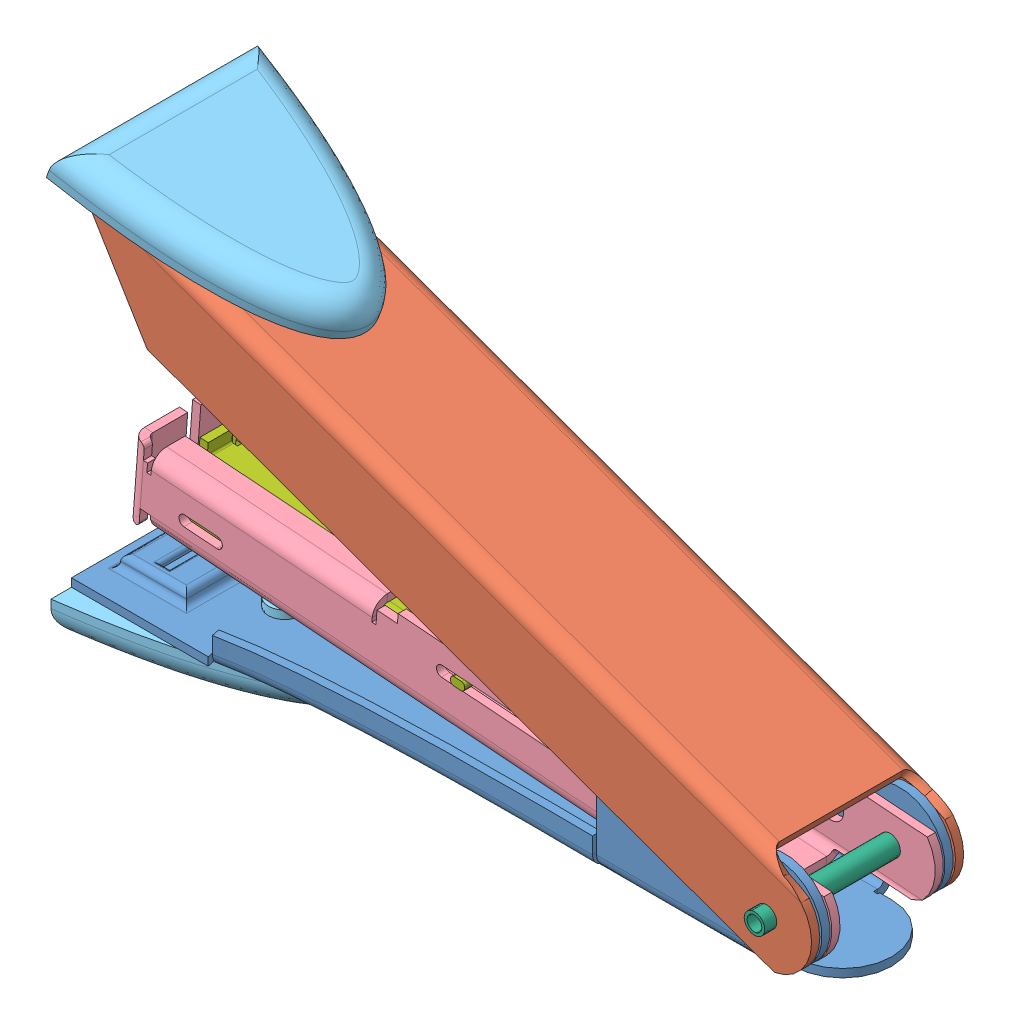
SolidWorks assembly Stapler Assembly, configuration Default. Lengths in mm.
Overall size (95.08 52.52 28.15).
8 component instances, 7 part files, 17 mates.
Components (placement in the parent):
- Stapler-1: Stapler [Default] at origin size (90 12.61 23.48)
- Stapler Top-1: Stapler Top [Default] at (5.6793 24.4276 0) x (-0.940839 0.338853 0) z (0 0 1) size (97 11.27 18.54)
- extruder-1: extruder [Default] at (8.6825 23.0271 -7) x (-0.940839 0.338853 0) z (0 0 1) size (63.3 11.3 14)
- Staples holder-1: Staples holder [Default] at (-39.6346 7.4288 0) x (0 0 -1) z (0.997127 -0.075744 0) size (13.6 9 86)
- Plastic part-1: Plastic part [Default] at (-34.6601 40.0191 0) x (0 0 -1) z (0.940839 -0.338853 0) size (28.15 6.5 38.91)
- Plastic part-2: Plastic part [buttom] at (-33.5362 -1 0) x (0 0 1) z (1 0 0) size (28.15 6 38.91)
- Staple pin-1: Staple pin [Default] at (40.9788 5.8683 -10.2654) x (0 0 1) z (-1 0 0) size (21 2.5 2.5)
- Staples Pusher-2: Staples Pusher [Default] at (6.8517 8.4105 0) x (-0.997127 0.075744 0) z (0 0 1) size (44.74 6 14)
Mates (geometry in assembly coordinates):
- Concentric1: concentric anti-aligned: cylinder of Stapler-1 through (40.9788 5.8683 8) axis (0 0 -1) radius 1.25; cylinder of Stapler Top-1 through (40.9788 5.8683 -9.2679) axis (0 0 1) radius 1.25
- Coincident2: coincident anti-aligned: plane of Stapler Top-1 through (5.6793 24.4276 0) normal (-0.338853 -0.940839 0); plane of extruder-1 through (8.0155 23.5862 -7) normal (0.338853 0.940839 0)
- Width1: width anti-aligned: plane of extruder-1 through (-35.7842 27.3506 4.5) normal (0 0 1); plane of extruder-1 through (-35.7842 27.3506 -4.5) normal (0 0 -1); plane of Stapler Top-1 through (8.6391 32.6455 8.2654) normal (0 0 -1); plane of Stapler Top-1 through (8.6391 32.6455 -8.2654) normal (0 0 1)
- Distance3: distance = 12 mm aligned: plane of extruder-1 through (-32.3947 36.7586 -7) normal (-0.940839 0.338853 0); plane of Stapler Top-1 through (-42.9055 42.9888 8.5) normal (-0.940839 0.338853 0)
- Concentric2: concentric anti-aligned: cylinder of Stapler Top-1 through (40.9788 5.8683 -9.2679) axis (0 0 1) radius 1.25; cylinder of Staples holder-1 through (40.9788 5.8683 5.8) axis (0 0 -1) radius 1.25
- Concentric3: concentric anti-aligned: cylinder of Stapler Top-1 through (-25.4609 46.2719 0) axis (-0.338853 -0.940839 0) radius 1.75; cylinder of Plastic part-1 through (-29.1883 35.9227 0) axis (0.338853 0.940839 0) radius 1.75
- Coincident8: coincident anti-aligned: plane of Stapler Top-1 through (6.0182 25.3684 0) normal (0.338853 0.940839 0); plane of Plastic part-1 through (-17.2205 33.7381 0) normal (-0.338853 -0.940839 0)
- Coincident9: coincident anti-aligned: plane of Stapler-1 through (41 -1 0) normal (0 -1 0); plane of Plastic part-2 through (-15 -1 0) normal (0 1 0)
- Concentric4: concentric anti-aligned: cylinder of Stapler-1 through (-27 -1 0) axis (0 1 0) radius 1.75; cylinder of Plastic part-2 through (-27 1 0) axis (0 -1 0) radius 1.75
- Coincident10: coincident aligned: plane of Stapler-1 through (-43 -1 -10) normal (-1 0 0); plane of Plastic part-2 through (-43 -5 -12.5) normal (-1 0 0)
- Parallel1: parallel aligned: plane of Stapler Top-1 through (-42.9055 42.9888 8.5) normal (-0.940839 0.338853 0); plane of Plastic part-1 through (-42.2086 46.9893 12.5) normal (-0.940839 0.338853 0)
- Concentric5: concentric anti-aligned: cylinder of Stapler-1 through (40.9788 5.8683 -8) axis (0 0 1) radius 1.25; cylinder of Staple pin-1 through (40.9788 5.8683 10.7346) axis (0 0 -1) radius 1.25
- Distance2: distance = 1 mm aligned: plane of Stapler Top-1 through (8.6391 32.6455 -9.2654) normal (0 0 -1); plane of Staple pin-1 through (40.9788 5.8683 -10.2654) normal (0 0 -1)
- Width5: width anti-aligned: plane of Staples Pusher-2 through (-37.9432 12.8162 3.8) normal (0.075744 0.997127 0); plane of Staples Pusher-2 through (-38.019 11.819 3.8) normal (-0.075744 -0.997127 0); plane of Staples holder-1 through (46.5463 6.5485 5.8) normal (-0.075744 -0.997127 0); plane of Staples holder-1 through (46.4479 5.2523 5.8) normal (0.075744 0.997127 0)
- Width6: width anti-aligned: plane of Stapler-1 through (0 0 7) normal (0 0 -1); plane of Stapler-1 through (0 0 -7) normal (0 0 1); plane of Staples holder-1 through (46.1941 1.9119 -5.8) normal (0 0 1); plane of Staples holder-1 through (46.7243 8.8918 5.8) normal (0 0 -1)
- Width7: width anti-aligned: plane of Stapler-1 through (0 0 7) normal (0 0 -1); plane of Stapler-1 through (0 0 -7) normal (0 0 1); plane of Stapler Top-1 through (8.6391 32.6455 -8.2654) normal (0 0 1); plane of Stapler Top-1 through (8.6391 32.6455 8.2654) normal (0 0 -1)
- Width8: width anti-aligned: plane of Staples Pusher-2 through (0.6001 9.2866 -7) normal (0 0 -1); plane of Staples Pusher-2 through (0.6001 9.2866 7) normal (0 0 1); plane of Staples holder-1 through (46.1941 1.9119 -5.8) normal (0 0 1); plane of Staples holder-1 through (46.7243 8.8918 5.8) normal (0 0 -1)
